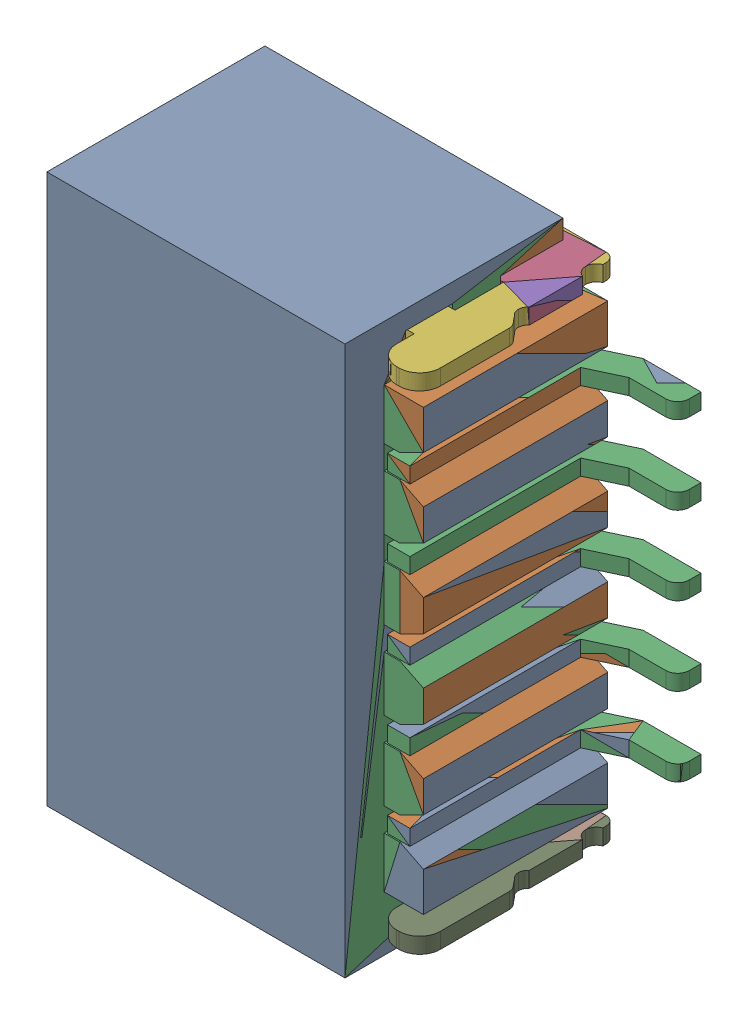
SolidWorks assembly CN5, configuration Défaut. Lengths in mm.
Overall size (5.2 7 3.14).
9 component instances, 6 part files, 0 mates.
Components (placement in the parent):
- A1002WR-S-5P-1: A1002WR-S-5P [Défaut] at (9.983 -9.4562 -1.6) x (0 -1 0) z (0 0 1) size (7 5.2 3.14)
- A1002WR-S-5P-2: A1002WR-S-5P [Défaut] at (9.983 -9.4562 -1.6) x (0 -1 0) z (0 0 1) size (7 5.2 3.14)
- A1002WR-S-5P_858-1: A1002WR-S-5P_858 [Défaut] at (9.983 -9.4562 -1.6) x (0 -1 0) z (0 0 1) size (7 5.2 3.14)
- A1002WR-S-5P_860-1: A1002WR-S-5P_860 [Défaut] at (9.983 -9.4562 -1.6) x (0 -1 0) z (0 0 1) size (0.2 4.22 2.68)
- A1002WR-S-5P_860-2: A1002WR-S-5P_860 [Défaut] at (9.983 -9.4562 -1.6) x (0 -1 0) z (0 0 1) size (0.2 4.22 2.68)
- A1002WR-S-5P_863-1: A1002WR-S-5P_863 [Défaut] at (9.983 -9.4562 -1.6) x (0 -1 0) z (0 0 1) size (0.2 4.22 2.68)
- A1002WR-S-5P_865-1: A1002WR-S-5P_865 [Défaut] at (9.983 -9.4562 -1.6) x (0 -1 0) z (0 0 1) size (0.2 4.22 2.68)
- A1002WR-S-5P_865-2: A1002WR-S-5P_865 [Défaut] at (9.983 -9.4562 -1.6) x (0 -1 0) z (0 0 1) size (0.2 4.22 2.68)
- A1002WR-S-5P_868-1: A1002WR-S-5P_868 [Défaut] at (9.983 -9.4562 -1.6) x (0 -1 0) z (0 0 1) size (0.2 4.22 2.68)
